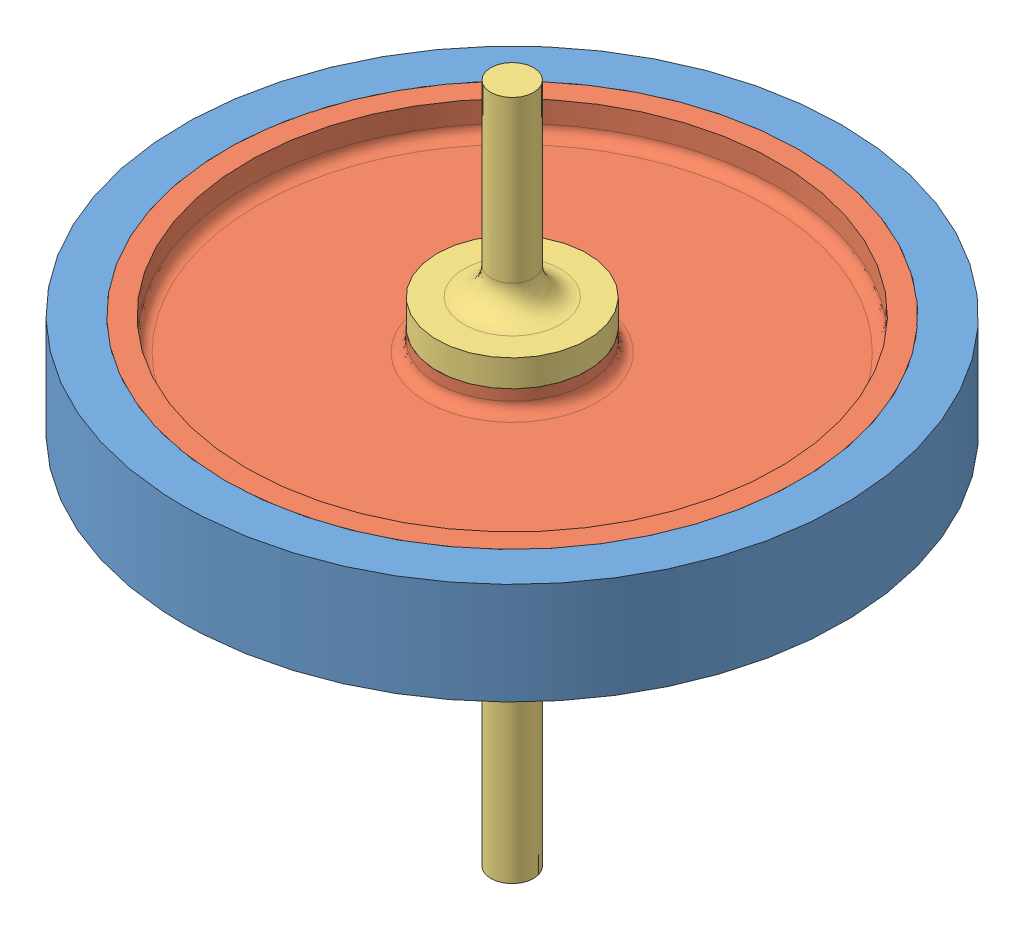
SolidWorks assembly wheelwithaxle, configuration Default. Lengths in mm.
Overall size (123 127 123).
3 component instances, 3 part files, 4 mates.
Components (placement in the parent):
- rim-1: rim [Default] at (-711.4248 -76.2879 334.1654) size (123 19 123)
- centre-1: centre [Default] at (-711.4248 -76.2879 334.1654) size (107 19 107)
- wheel axle-1: wheel axle [Default] at (-713.6031 -81.7741 334.1654) size (28 127 28)
Mates (geometry in assembly coordinates):
- Concentric1: concentric: cylinder of rim-1 through (-711.4248 -57.2879 334.1654) axis (0 -1 0) radius 53.5; cylinder of centre-1 through (-711.4248 -21.1087 334.1654) axis (0 -1 0) radius 53.5
- Coincident1: coincident aligned: plane of rim-1 through (-711.4248 -57.2879 334.1654) normal (0 1 0); plane of centre-1 through (-711.4248 -57.2879 334.1654) normal (0 1 0)
- Concentric3: concentric: cylinder of centre-1 through (-711.4248 -76.2879 334.1654) axis (0 1 0) radius 6; cylinder of wheel axle-1 through (-711.4248 -19.2879 334.1654) axis (0 1 0) radius 4
- Coincident2: coincident aligned: plane of centre-1 through (-711.4248 -59.2879 334.1654) normal (0 1 0); circle of wheel axle-1
